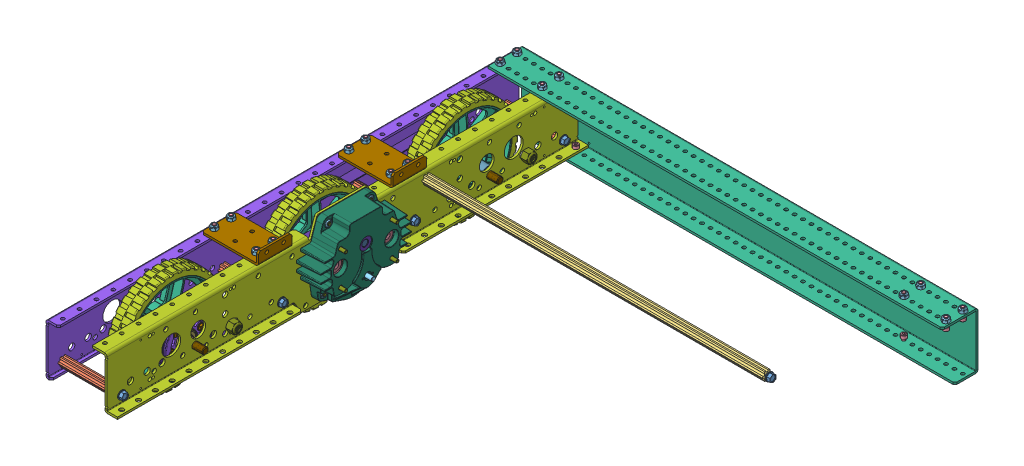
SolidWorks assembly AM14U3Square_Half, configuration Default. Lengths in mm.
Overall size (698.32 218.82 715.14).
150 component instances, 36 part files, 25 mates.
Components (placement in the parent):
- AM14U3Square_Frame_Half-1: AM14U3Square_Frame_Half [Default] at (326.068 37.2757 -291.2758) size (697.74 116.33 715.14)
  - ThreadRollingScrew_0.25-20x0.75-1: ThreadRollingScrew_0.25-20x0.75 [FHTS 0.25-20-G-0.75-C] at (-600.075 -67.437 693.039) x (-1 0 0) z (0 0.924225 0.381849) size (24.64 12.19 12.19)
  - ThreadRollingScrew_0.25-20x0.75-4: ThreadRollingScrew_0.25-20x0.75 [FHTS 0.25-20-G-0.75-C] at (-600.075 -67.437 26.035) x (-1 0 0) z (0 0.717495 0.696564) size (24.64 12.19 12.19)
  - ThreadRollingScrew_0.25-20x0.75-5: ThreadRollingScrew_0.25-20x0.75 [FHTS 0.25-20-G-0.75-C] at (-692.15 -67.437 26.162) size (24.64 12.19 12.19)
  - ThreadRollingScrew_0.25-20x0.75-7: ThreadRollingScrew_0.25-20x0.75 [FHTS 0.25-20-G-0.75-C] at (-603.25 -15.24 232.537) x (1 0 0) z (0 0.687398 0.726281) size (24.64 12.19 12.19)
  - ThreadRollingScrew_0.25-20x0.75-9: ThreadRollingScrew_0.25-20x0.75 [FHTS 0.25-20-G-0.75-C] at (-692.15 -67.437 692.912) size (24.64 12.19 12.19)
  - ThreadRollingScrew_0.25-20x0.75-10: ThreadRollingScrew_0.25-20x0.75 [FHTS 0.25-20-G-0.75-C] at (-82.55 -15.24 232.537) x (-1 0 0) z (0 0.525103 -0.851039) size (24.64 12.19 12.19)
  - 500Churro_3.375-1: 500Churro_3.375 [Default] at (-603.25 -67.437 26.162) x (0 -0.866025 0.5) z (-1 0 0) size (14.66 12.7 85.72)
  - 500Churro_3.375-2: 500Churro_3.375 [Default] at (-603.25 -67.437 692.912) x (0 -0.866025 0.5) z (-1 0 0) size (14.66 12.7 85.72)
  - 500Churro_cut_20.25-1: 500Churro_cut_20.25 [Default] at (-85.725 -15.24 232.537) x (0 0 -1) z (-1 0 0) size (14.66 12.7 514.35)
  - Screw_SHCS_10-32x0.5-19: Screw_SHCS_10-32x0.5 [HX-SHCS 0.19-32x1.375x1-C] at (-679.45 -11.176 42.037) x (0 1 0) z (0.542711 0 0.839919) size (17.53 7.94 7.94)
  - Screw_SHCS_10-32x0.5-20: Screw_SHCS_10-32x0.5 [HX-SHCS 0.19-32x1.375x1-C] at (-679.45 -11.176 16.637) x (0 1 0) z (0.127767 0 0.991804) size (17.53 7.94 7.94)
  - Screw_SHCS_10-32x0.5-21: Screw_SHCS_10-32x0.5 [HX-SHCS 0.19-32x1.375x1-C] at (-615.95 -11.176 16.637) x (0 1 0) z (0 0 1) size (17.53 7.94 7.94)
  - Screw_SHCS_10-32x0.5-22: Screw_SHCS_10-32x0.5 [HX-SHCS 0.19-32x1.375x1-C] at (-615.95 -11.176 42.037) x (0 1 0) z (0.337423 0 -0.941353) size (17.53 7.94 7.94)
  - Screw_SHCS_10-32x0.5-23: Screw_SHCS_10-32x0.5 [HX-SHCS 0.19-32x1.375x1-C] at (-590.55 -72.898 16.637) x (0 -1 0) z (0.717151 0 -0.696918) size (17.53 7.94 7.94)
  - Screw_SHCS_10-32x0.5-24: Screw_SHCS_10-32x0.5 [HX-SHCS 0.19-32x1.375x1-C] at (-6.35 -11.176 16.637) x (0 1 0) z (0.222581 0 0.974914) size (17.53 7.94 7.94)
  - Screw_SHCS_10-32x0.5-25: Screw_SHCS_10-32x0.5 [HX-SHCS 0.19-32x1.375x1-C] at (-6.35 -11.176 42.037) x (0 1 0) z (0.81526 0 0.579096) size (17.53 7.94 7.94)
  - Screw_SHCS_10-32x0.5-26: Screw_SHCS_10-32x0.5 [HX-SHCS 0.19-32x1.375x1-C] at (-69.85 -11.176 16.637) x (0 1 0) z (0 0 1) size (17.53 7.94 7.94)
  - Screw_SHCS_10-32x0.5-27: Screw_SHCS_10-32x0.5 [HX-SHCS 0.19-32x1.375x1-C] at (-69.85 -11.176 42.037) x (0 1 0) z (0.111454 0 0.99377) size (17.53 7.94 7.94)
  - Screw_SHCS_10-32x0.5-28: Screw_SHCS_10-32x0.5 [HX-SHCS 0.19-32x1.375x1-C] at (-95.25 -73.406 16.637) x (0 -1 0) z (0.007214 0 0.999974) size (17.53 7.94 7.94)
  - NylockNut_10-32-19: NylockNut_10-32 [Default] at (-679.45 0 42.037) x (0.996106 0 -0.088165) z (0 1 0) size (10.18 11.01 7.1)
  - NylockNut_10-32-21: NylockNut_10-32 [Default] at (-679.45 0 16.637) x (1 0 0) z (0 1 0) size (10.18 11.01 7.1)
  - NylockNut_10-32-22: NylockNut_10-32 [Default] at (-615.95 0 42.037) x (1 0 0) z (0 1 0) size (10.18 11.01 7.1)
  - NylockNut_10-32-23: NylockNut_10-32 [Default] at (-615.95 0 16.637) x (-0.398852 0 -0.917015) z (0 1 0) size (10.18 11.01 7.1)
  - NylockNut_10-32-25: NylockNut_10-32 [Default] at (-69.85 0 42.037) x (1 0 0) z (0 1 0) size (10.18 11.01 7.1)
  - NylockNut_10-32-26: NylockNut_10-32 [Default] at (-69.85 0 16.637) x (1 0 0) z (0 1 0) size (10.18 11.01 7.1)
  - NylockNut_10-32-27: NylockNut_10-32 [Default] at (-6.35 0 42.037) x (1 0 0) z (0 1 0) size (10.18 11.01 7.1)
  - NylockNut_10-32-28: NylockNut_10-32 [Default] at (-6.35 0 16.637) x (1 0 0) z (0 1 0) size (10.18 11.01 7.1)
  - NylockNut_10-32-29: NylockNut_10-32 [Default] at (-95.25 -84.582 16.637) x (1 0 0) z (0 -1 0) size (10.18 11.01 7.1)
  - NylockNut_10-32-30: NylockNut_10-32 [Default] at (-590.55 -84.582 16.637) x (1 0 0) z (0 -1 0) size (10.18 11.01 7.1)
  - Screw_SHCS_10-32x0.5-29: Screw_SHCS_10-32x0.5 [HX-SHCS 0.19-32x1.375x1-C] at (-679.45 -11.176 245.237) x (0 1 0) z (0.717626 0 0.696429) size (17.53 7.94 7.94)
  - Screw_SHCS_10-32x0.5-30: Screw_SHCS_10-32x0.5 [HX-SHCS 0.19-32x1.375x1-C] at (-679.45 -11.176 270.637) x (0 1 0) z (-0.597439 0 0.801914) size (17.53 7.94 7.94)
  - Screw_SHCS_10-32x0.5-31: Screw_SHCS_10-32x0.5 [HX-SHCS 0.19-32x1.375x1-C] at (-615.95 -11.176 245.237) x (0 1 0) z (0.931086 0 -0.3648) size (17.53 7.94 7.94)
  - Screw_SHCS_10-32x0.5-32: Screw_SHCS_10-32x0.5 [HX-SHCS 0.19-32x1.375x1-C] at (-615.95 -11.176 270.637) x (0 1 0) z (0.782299 0 0.622903) size (17.53 7.94 7.94)
  - Screw_SHCS_10-32x0.5-33: Screw_SHCS_10-32x0.5 [HX-SHCS 0.19-32x1.375x1-C] at (-615.95 -11.176 448.437) x (0 1 0) z (0 0 1) size (17.53 7.94 7.94)
  - Screw_SHCS_10-32x0.5-34: Screw_SHCS_10-32x0.5 [HX-SHCS 0.19-32x1.375x1-C] at (-615.95 -11.176 473.837) x (0 1 0) z (0 0 1) size (17.53 7.94 7.94)
  - Screw_SHCS_10-32x0.5-35: Screw_SHCS_10-32x0.5 [HX-SHCS 0.19-32x1.375x1-C] at (-679.45 -11.176 448.437) x (0 1 0) z (0 0 1) size (17.53 7.94 7.94)
  - Screw_SHCS_10-32x0.5-36: Screw_SHCS_10-32x0.5 [HX-SHCS 0.19-32x1.375x1-C] at (-679.45 -11.176 473.837) x (0 1 0) z (0 0 1) size (17.53 7.94 7.94)
  - NylockNut_10-32-31: NylockNut_10-32 [Default] at (-679.45 0 473.837) x (1 0 0) z (0 1 0) size (10.18 11.01 7.1)
  - NylockNut_10-32-32: NylockNut_10-32 [Default] at (-679.45 0 448.437) x (1 0 0) z (0 1 0) size (10.18 11.01 7.1)
  - NylockNut_10-32-33: NylockNut_10-32 [Default] at (-615.95 0 448.437) x (1 0 0) z (0 1 0) size (10.18 11.01 7.1)
  - NylockNut_10-32-34: NylockNut_10-32 [Default] at (-615.95 0 473.837) x (1 0 0) z (0 1 0) size (10.18 11.01 7.1)
  - NylockNut_10-32-35: NylockNut_10-32 [Default] at (-679.45 0 270.637) x (1 0 0) z (0 1 0) size (10.18 11.01 7.1)
  - NylockNut_10-32-37: NylockNut_10-32 [Default] at (-679.45 0 245.237) x (1 0 0) z (0 1 0) size (10.18 11.01 7.1)
  - NylockNut_10-32-38: NylockNut_10-32 [Default] at (-615.95 0 270.637) x (-0.99946 0 -0.032874) z (0 1 0) size (10.18 11.01 7.1)
  - NylockNut_10-32-39: NylockNut_10-32 [Default] at (-615.95 0 245.237) x (-0.973817 0 0.227332) z (0 1 0) size (10.18 11.01 7.1)
  - AM14U3EndPlate_Square-1: AM14U3EndPlate_Square [Default] at (-787.4 -81.407 0) x (1 0 0) z (0 -1 0) size (685.8 53.98 84.58)
  - AM14U3InnerPlate_Square-1: AM14U3InnerPlate_Square [Default] at (-603.25 -76.962 765.937) x (0 0 -1) z (0 -1 0) size (711.2 38.1 116.33)
  - AM14U3OuterPlate_Square-1: AM14U3OuterPlate_Square [Default] at (-667.7485 -26.7681 75.5865) x (0 0 1) z (0 -1 0) size (711.2 19.05 77.72)
  - Bracket_2x3-1: Bracket_2x3 [Default] at (-685.8 -3.175 499.237) size (85.72 19.05 50.8)
  - Bracket_2x3-2: Bracket_2x3 [Default] at (-685.8 -3.175 296.037) size (85.72 19.05 50.8)
  - 500Churro_3.375-5: 500Churro_3.375 [Default] at (-688.975 -66.675 451.612) x (0 0 -1) z (1 0 0) size (14.66 12.7 85.72)
  - 500Churro_3.375-6: 500Churro_3.375 [Default] at (-688.975 -59.4147 252.0115) x (0 0.995852 0.090991) z (1 0 0) size (14.66 12.7 85.72)
  - ThreadRollingScrew_0.25-20x0.75-11: ThreadRollingScrew_0.25-20x0.75 [FHTS 0.25-20-G-0.75-C] at (-600.075 -66.675 451.612) x (-1 0 0) z (0 0.997671 0.06821) size (24.64 12.19 12.19)
  - ThreadRollingScrew_0.25-20x0.75-12: ThreadRollingScrew_0.25-20x0.75 [FHTS 0.25-20-G-0.75-C] at (-600.075 -59.4147 252.0115) x (-1 0 0) z (0 -0.62596 0.779855) size (24.64 12.19 12.19)
  - ThreadRollingScrew_0.25-20x0.75-13: ThreadRollingScrew_0.25-20x0.75 [FHTS 0.25-20-G-0.75-C] at (-692.15 -66.675 451.612) size (24.64 12.19 12.19)
  - ThreadRollingScrew_0.25-20x0.75-14: ThreadRollingScrew_0.25-20x0.75 [FHTS 0.25-20-G-0.75-C] at (-692.15 -66.675 267.462) size (24.64 12.19 12.19)
- ToughboxMini-1: ToughboxMini [Default] at (-324.5487 -32.4844 159.362) x (0 0.001296 0.999999) z (-1 0 0) size (140.05 122.78 142.29) (flexible)
  - TBMiniSmallHexShaft-1: TBMiniSmallHexShaft [Default] at (-75.0534 90.4124 -52.3959) x (-0.017391 0.999849 0) z (0.999849 0.017391 0) size (11 38.23 9.52)
  - LargeClusterGear_Hex_50t0.375-1: LargeClusterGear_Hex_50t0.375 [Default] at (-91.0349 50.9043 -67.5597) x (-0.017391 0.999849 0) z (0 0 -1) size (65.97 66.04 10.16)
  - Bearing_FR6ZZ-1: Bearing_FR6ZZ [Default] at (-96.247 60.278 -52.5991) x (-0.893862 0.448342 0) z (0 0 1) size (24.69 24.69 7.16)
  - NylockNut_10-32-1: NylockNut_10-32 [Default] at (-129.8464 -8.0737 -56.3837) x (0.501678 0.865055 0) z (0 0 -1) size (10.18 11.01 7.1)
  - NylockNut_10-32-2: NylockNut_10-32 [Default] at (-59.2462 80.7349 -56.3837) x (0.999999 -0.001296 0) z (0 0 -1) size (10.18 11.01 7.1)
  - NylockNut_10-32-3: NylockNut_10-32 [Default] at (-122.7461 80.8172 -56.3837) x (0.500567 0.865698 0) z (0 0 -1) size (10.18 11.01 7.1)
  - NylockNut_10-32-4: NylockNut_10-32 [Default] at (-52.3764 -8.1741 -56.3837) x (-0.501678 -0.865055 0) z (0 0 -1) size (10.18 11.01 7.1)
  - Washer_5-16-1: Washer_5-16 [Default] at (-52.3162 38.3079 -77.7705) x (-0.418041 0.908428 0) z (0 0 -1) size (17.53 17.53 1.47)
  - Washer_5-16-2: Washer_5-16 [Default] at (-52.3162 38.3079 -76.2973) x (0.897267 -0.441488 0) z (0 0 -1) size (17.53 17.53 1.47)
  - Washer_5-16-3: Washer_5-16 [Default] at (-129.7861 38.4083 -77.7705) x (-0.990116 0.140253 0) z (0 0 1) size (17.53 17.53 1.47)
  - Washer_5-16-4: Washer_5-16 [Default] at (-129.7861 38.4083 -79.2437) x (-0.681761 0.731575 0) z (0 0 1) size (17.53 17.53 1.47)
  - CIMGear_14t8mm-1: CIMGear_14t8mm [Default] at (-52.3162 38.3079 -63.5973) x (0.95671 0.291041 0) z (0 0 -1) size (20.03 20.32 12.7)
  - CIMGear_14t8mm-2: CIMGear_14t8mm [Default] at (-129.7861 38.4083 -63.5973) x (0.906804 -0.421552 0) z (0 0 -1) size (20.03 20.32 12.7)
  - TBMiniHousing-1: TBMiniHousing [Default] at (-91.0876 10.1882 -86.3557) x (0.999999 -0.001296 0) z (0 0 1) size (139.9 118.55 41.54)
  - Screw_SHCS_10-32x0.625-1: Screw_SHCS_10-32x0.625 [Default] at (-52.2832 63.7078 -74.4685) x (-0.564778 -0.825243 0) z (-0.825243 0.564778 0) size (7.82 20.65 7.82)
  - Screw_SHCS_10-32x0.625-2: Screw_SHCS_10-32x0.625 [Default] at (-122.7461 80.8172 -42.5915) x (0.507484 -0.861661 0) z (-0.861661 -0.507484 0) size (7.82 20.65 7.82)
  - Screw_SHCS_10-32x0.625-3: Screw_SHCS_10-32x0.625 [Default] at (-52.3764 -8.1741 -42.5915) x (0.507484 -0.861661 0) z (-0.861661 -0.507484 0) size (7.82 20.65 7.82)
  - Screw_SHCS_10-32x0.625-4: Screw_SHCS_10-32x0.625 [Default] at (-129.8464 -8.0737 -42.5915) x (0.507484 -0.861661 0) z (-0.861661 -0.507484 0) size (7.82 20.65 7.82)
  - Screw_SHCS_10-32x0.625-5: Screw_SHCS_10-32x0.625 [Default] at (-59.2462 80.7349 -42.5915) x (0.740711 -0.671824 0) z (-0.671824 -0.740711 0) size (7.82 20.65 7.82)
  - Screw_SHCS_10-32x0.625-6: Screw_SHCS_10-32x0.625 [Default] at (-52.3491 12.9079 -74.4685) x (-0.564778 -0.825243 0) z (-0.825243 0.564778 0) size (7.82 20.65 7.82)
  - Screw_SHCS_10-32x0.625-7: Screw_SHCS_10-32x0.625 [Default] at (-129.7532 63.8083 -74.4685) x (-0.966277 -0.257503 0) z (-0.257503 0.966277 0) size (7.82 20.65 7.82)
  - Screw_SHCS_10-32x0.625-8: Screw_SHCS_10-32x0.625 [Default] at (-129.819 13.0083 -74.4685) x (-0.99652 0.083357 0) z (0.083357 0.99652 0) size (7.82 20.65 7.82)
  - Bearing_R6ZZ-3: Bearing_R6ZZ [Default] at (-91.0349 50.9043 -84.8317) x (0.958138 -0.286306 0) z (0 0 1) size (22.23 22.23 7.11)
  - Bearing_R6ZZ-4: Bearing_R6ZZ [Default] at (-91.0876 10.1882 -84.8317) x (-0.661529 0.74992 0) z (0 0 1) size (22.23 22.23 7.11)
  - RetainingClip-1: RetainingClip [Default] at (-129.7861 38.4083 -63.5973) x (0 0 1) z (-1 0 0) size (1.09 14.83 14.83)
  - RetainingClip-2: RetainingClip [Default] at (-52.3162 38.3079 -63.5973) x (0 0 1) z (-1 0 0) size (1.09 14.83 14.83)
  - ExternalKlipring-1: ExternalKlipring [Default] at (-91.0876 10.1882 -64.4355) x (0.996411 -0.084651 0) z (0 0 1) size (19.07 20.96 1.27)
  - HexBearing_FR8ZZ-1: HexBearing_FR8ZZ [Default] at (-91.0876 10.1882 -44.6717) x (0.029036 0.999578 0) z (0 0 -1) size (31.12 31.12 7.93)
  - SmallClusterGear_Hex_16t0.375-1: SmallClusterGear_Hex_16t0.375 [Default] at (-91.0349 50.9043 -67.5597) x (0 0 1) z (-0.87459 0.484863 0) size (15.19 22.57 22.57)
  - LargeOutputGear_Hex_48t0.5-1: LargeOutputGear_Hex_48t0.5 [Default] at (-91.0876 10.1882 -63.1655) x (0 0 1) z (-0.880178 -0.474644 0) size (10.21 63.42 63.42)
  - TBMiniHexOutputShaft-2: TBMiniHexOutputShaft [Default] at (-73.3134 47.9951 -52.3197) x (0.029036 0.999578 0) z (0.999578 -0.029036 0) size (14.66 142.29 12.7)
- Wheel_6inHiGrip_Center-1: Wheel_6inHiGrip_Center [Default] at (-288.1818 -17.7898 -84.7378) x (-1 0 0) z (0 0.475784 0.879562) size (81.42 191.55 191.55) (flexible)
  - Wheel_6inHiGrip-1: Wheel_6inHiGrip [Default] at (83.7987 67.439 110.9939) size (35.05 191.55 191.55)
    - Wheel_6inHiGrip_Wheel-1: Wheel_6inHiGrip_Wheel [Default] at (-52.6446 9.4231 21.378) size (35.05 132.08 132.08)
    - Wheel_6inHiGrip_Tread-1: Wheel_6inHiGrip_Tread [Default] at (-65.3446 9.4231 21.378) x (0 -0.304368 -0.952555) z (1 0 0) size (152.4 152.4 25.58)
  - HalfPulley_42t5mm-1: HalfPulley_42t5mm [Default] at (47.6006 76.862 132.3719) x (1 0 0) z (0 -0.5 0.866025) size (13 74.23 74.23)
  - HalfPulley_42t5mm-2: HalfPulley_42t5mm [Default] at (64.263 76.862 132.3719) x (-1 0 0) z (0 -0.499927 0.866067) size (13 74.23 74.23)
  - ThreadFormingScrew_10-24x1.25-1: ThreadFormingScrew_10-24x1.25 [93882A213] at (63.247 76.8605 108.5602) x (0 -0.67777 0.735274) z (1 0 0) size (10.52 10.52 35.59)
  - ThreadFormingScrew_10-24x1.25-2: ThreadFormingScrew_10-24x1.25 [93882A213] at (63.247 97.4833 120.4656) x (0 -0.67777 0.735274) z (1 0 0) size (10.52 10.52 35.59)
  - ThreadFormingScrew_10-24x1.25-3: ThreadFormingScrew_10-24x1.25 [93882A213] at (63.247 56.2398 144.2799) x (0 -0.67777 0.735274) z (1 0 0) size (10.52 10.52 35.59)
  - ThreadFormingScrew_10-24x1.25-4: ThreadFormingScrew_10-24x1.25 [93882A213] at (63.247 76.8625 156.1852) x (0 0.509671 0.860369) z (1 0 0) size (10.52 10.52 35.59)
  - ThreadFormingScrew_10-24x1.25-5: ThreadFormingScrew_10-24x1.25 [93882A213] at (63.247 97.4843 144.2781) x (0 0.974333 0.225112) z (1 0 0) size (10.52 10.52 35.59)
  - ThreadFormingScrew_10-24x1.25-6: ThreadFormingScrew_10-24x1.25 [93882A213] at (63.247 56.2388 120.4674) x (0 0.101244 0.994862) z (1 0 0) size (10.52 10.52 35.59)
  - HalfPulley_42t5mm-3: HalfPulley_42t5mm [Default] at (-1.9548 76.862 132.3719) x (1 0 0) z (0 -1 -0.000063) size (13 74.23 74.23)
  - HalfPulley_42t5mm-4: HalfPulley_42t5mm [Default] at (14.7076 76.862 132.3719) x (-1 0 0) z (0 -1 0.000021) size (13 74.23 74.23)
  - HexHub_500EX-1: HexHub_500EX [Default] at (-8.3048 76.862 132.3719) x (0 -0.866025 -0.5) z (0 -0.5 0.866025) size (55.37 25.4 51.33)
  - ThreadFormingScrew_10-24x1.25-7: ThreadFormingScrew_10-24x1.25 [93882A213] at (-5.2568 97.4843 120.4656) x (0 0.67777 -0.735274) z (-1 0 0) size (10.52 10.52 35.59)
  - ThreadFormingScrew_10-24x1.25-8: ThreadFormingScrew_10-24x1.25 [93882A213] at (-5.2568 76.862 108.5594) x (0 0.67777 -0.735274) z (-1 0 0) size (10.52 10.52 35.59)
  - ThreadFormingScrew_10-24x1.25-9: ThreadFormingScrew_10-24x1.25 [93882A213] at (-5.2568 56.2398 120.4656) x (0 0.67777 -0.735274) z (-1 0 0) size (10.52 10.52 35.59)
  - ThreadFormingScrew_10-24x1.25-10: ThreadFormingScrew_10-24x1.25 [93882A213] at (-5.2568 97.4843 144.2781) x (0 0.654955 0.755668) z (-1 0 0) size (10.52 10.52 35.59)
  - ThreadFormingScrew_10-24x1.25-11: ThreadFormingScrew_10-24x1.25 [93882A213] at (-5.2568 56.2398 144.2781) x (0 0.773336 -0.633996) z (-1 0 0) size (10.52 10.52 35.59)
  - ThreadFormingScrew_10-24x1.25-12: ThreadFormingScrew_10-24x1.25 [93882A213] at (-5.2568 76.862 156.1844) x (0 0.622324 0.782759) z (-1 0 0) size (10.52 10.52 35.59)
  - Spacer_Hex_0.57x0.5-1: Spacer_Hex_0.57x0.5 [Default] at (57.8495 76.862 132.3719) x (0 -0.866025 -0.5) z (0 -0.5 0.866025) size (28.55 14.48 28.55)
- Wheel-6inHiGrip_Outer-1: Wheel-6inHiGrip_Outer [Default] at (-351.6685 85.441 180.4563) x (1 0 0) z (0 -0.96131 0.275469) size (85.56 191.55 191.55)
  - Wheel_6inHiGrip-1: Wheel_6inHiGrip [Default] at (83.7987 67.439 110.9939) size (35.05 191.55 191.55)
    - Wheel_6inHiGrip_Wheel-1: Wheel_6inHiGrip_Wheel [Default] at (-52.6446 9.4231 21.378) size (35.05 132.08 132.08)
    - Wheel_6inHiGrip_Tread-1: Wheel_6inHiGrip_Tread [Default] at (-65.3446 9.4231 21.378) x (0 -0.304368 -0.952555) z (1 0 0) size (152.4 152.4 25.58)
  - HalfPulley_42t5mm-1: HalfPulley_42t5mm [Default] at (47.6006 76.862 132.3719) x (1 0 0) z (0 -0.5 0.866025) size (13 74.23 74.23)
  - HalfPulley_42t5mm-2: HalfPulley_42t5mm [Default] at (64.263 76.862 132.3719) x (-1 0 0) z (0 -0.499927 0.866067) size (13 74.23 74.23)
  - Bearing_1614ZZ-1: Bearing_1614ZZ [Default] at (62.612 76.862 132.3719) x (0 -0.157148 -0.987575) z (-1 0 0) size (28.57 28.57 9.53)
  - Bearing_1614ZZ-2: Bearing_1614ZZ [Default] at (15.2791 76.862 132.3719) x (0 0 -1) z (1 0 0) size (28.57 28.57 9.53)
  - ThreadFormingScrew_10-24x1.25-1: ThreadFormingScrew_10-24x1.25 [93882A213] at (63.247 76.8605 108.5602) x (0 0 -1) z (1 0 0) size (10.52 10.52 35.59)
  - ThreadFormingScrew_10-24x1.25-2: ThreadFormingScrew_10-24x1.25 [93882A213] at (63.247 97.4833 120.4656) x (0 0 -1) z (1 0 0) size (10.52 10.52 35.59)
  - ThreadFormingScrew_10-24x1.25-3: ThreadFormingScrew_10-24x1.25 [93882A213] at (63.247 56.2398 144.2799) x (0 0 -1) z (1 0 0) size (10.52 10.52 35.59)
  - ThreadFormingScrew_10-24x1.25-4: ThreadFormingScrew_10-24x1.25 [93882A213] at (63.247 76.8625 156.1852) x (0 -0.95788 -0.287168) z (1 0 0) size (10.52 10.52 35.59)
  - ThreadFormingScrew_10-24x1.25-5: ThreadFormingScrew_10-24x1.25 [93882A213] at (63.247 97.4843 144.2781) x (0 -0.868976 0.494854) z (1 0 0) size (10.52 10.52 35.59)
  - ThreadFormingScrew_10-24x1.25-6: ThreadFormingScrew_10-24x1.25 [93882A213] at (63.247 56.2388 120.4674) x (0 -0.977348 -0.211637) z (1 0 0) size (10.52 10.52 35.59)
  - Spacer_0.28x0.382-1: Spacer_0.28x0.382 [Default] at (74.4865 76.862 132.3719) x (0 -0.35357 0.935408) z (-1 0 0) size (13.16 13.16 7.11)
  - Spacer_0.85x0.38-1: Spacer_0.85x0.38 [Default] at (-11.0734 76.862 132.3719) x (0 0 -1) z (1 0 0) size (19.05 19.05 21.59)
- Wheel-6inHiGrip_Outer-2: Wheel-6inHiGrip_Outer [Default] at (-288.2554 114.8369 -225.5401) x (-1 0 0) z (0 -0.531631 0.846976) size (85.56 191.55 191.55)
  - Wheel_6inHiGrip-1: Wheel_6inHiGrip [Default] at (83.7987 67.439 110.9939) size (35.05 191.55 191.55)
    - Wheel_6inHiGrip_Wheel-1: Wheel_6inHiGrip_Wheel [Default] at (-52.6446 9.4231 21.378) size (35.05 132.08 132.08)
    - Wheel_6inHiGrip_Tread-1: Wheel_6inHiGrip_Tread [Default] at (-65.3446 9.4231 21.378) x (0 -0.304368 -0.952555) z (1 0 0) size (152.4 152.4 25.58)
  - HalfPulley_42t5mm-1: HalfPulley_42t5mm [Default] at (47.6006 76.862 132.3719) x (1 0 0) z (0 -0.5 0.866025) size (13 74.23 74.23)
  - HalfPulley_42t5mm-2: HalfPulley_42t5mm [Default] at (64.263 76.862 132.3719) x (-1 0 0) z (0 -0.499927 0.866067) size (13 74.23 74.23)
  - Bearing_1614ZZ-1: Bearing_1614ZZ [Default] at (62.612 76.862 132.3719) x (0 -0.157148 -0.987575) z (-1 0 0) size (28.57 28.57 9.53)
  - Bearing_1614ZZ-2: Bearing_1614ZZ [Default] at (15.2791 76.862 132.3719) x (0 0 -1) z (1 0 0) size (28.57 28.57 9.53)
  - ThreadFormingScrew_10-24x1.25-1: ThreadFormingScrew_10-24x1.25 [93882A213] at (63.247 76.8605 108.5602) x (0 0 -1) z (1 0 0) size (10.52 10.52 35.59)
  - ThreadFormingScrew_10-24x1.25-2: ThreadFormingScrew_10-24x1.25 [93882A213] at (63.247 97.4833 120.4656) x (0 0 -1) z (1 0 0) size (10.52 10.52 35.59)
  - ThreadFormingScrew_10-24x1.25-3: ThreadFormingScrew_10-24x1.25 [93882A213] at (63.247 56.2398 144.2799) x (0 0 -1) z (1 0 0) size (10.52 10.52 35.59)
  - ThreadFormingScrew_10-24x1.25-4: ThreadFormingScrew_10-24x1.25 [93882A213] at (63.247 76.8625 156.1852) x (0 -0.95788 -0.287168) z (1 0 0) size (10.52 10.52 35.59)
  - ThreadFormingScrew_10-24x1.25-5: ThreadFormingScrew_10-24x1.25 [93882A213] at (63.247 97.4843 144.2781) x (0 -0.868976 0.494854) z (1 0 0) size (10.52 10.52 35.59)
  - ThreadFormingScrew_10-24x1.25-6: ThreadFormingScrew_10-24x1.25 [93882A213] at (63.247 56.2388 120.4674) x (0 -0.977348 -0.211637) z (1 0 0) size (10.52 10.52 35.59)
  - Spacer_0.28x0.382-1: Spacer_0.28x0.382 [Default] at (74.4865 76.862 132.3719) x (0 -0.35357 0.935408) z (-1 0 0) size (13.16 13.16 7.11)
  - Spacer_0.85x0.38-1: Spacer_0.85x0.38 [Default] at (-11.0734 76.862 132.3719) x (0 0 -1) z (1 0 0) size (19.05 19.05 21.59)
- Bearing_Hex_FR8ZZ-1: Bearing_Hex_FR8ZZ [Default] at (-369.3104 -22.4143 68.2612) x (0 -0.523831 0.851822) z (1 0 0) size (31.12 31.12 7.93)
- NylockNut_0.375-16-1: NylockNut_0.375-16 [91831A127] at (-274.007 -20.8903 236.8339) x (0 -1 0) z (0 0 1) size (14.29 12 16.5)
- NylockNut_0.375-16-2: NylockNut_0.375-16 [91831A127] at (-274.007 -20.8903 -208.2615) x (0 -1 0) z (0 0 1) size (14.29 12 16.5)
- Belt_15mm_Square-1: Belt_15mm_Square [Default] at (-289.0679 -20.6363 290.8089) x (0 -0.007989 -0.999968) z (-1 0 0) size (291.74 69.19 15)
- Belt_15mm_Square-2: Belt_15mm_Square [Default] at (-335.856 -20.6363 -154.2865) x (0 -0.007989 0.999968) z (-1 0 0) size (291.74 69.19 15)
- HHSBolt_0.375-16x4.25-3: HHSBolt_0.375-16x4.25 [HFBOLT 0.375-16x2.5x1-C] at (-372.2542 -20.6363 290.8089) x (1 0 0) z (0 0.54705 -0.8371) size (114.12 16.48 14.27)
- HHSBolt_0.375-16x4.25-4: HHSBolt_0.375-16x4.25 [HFBOLT 0.375-16x2.5x1-C] at (-372.2542 -20.6363 -154.2865) x (1 0 0) z (0 -0.961423 -0.275075) size (114.12 16.48 14.27)
Mates (geometry in assembly coordinates):
- Concentric1: concentric anti-aligned: cylinder of ToughboxMini-1/HexBearing_FR8ZZ-1 through (-271.9496 -22.4143 68.2612) axis (-1 0 0) radius 14.2875; cylinder of AM14U3Square_Frame_Half-1/AM14U3InnerPlate_Square-1 through (-277.182 -22.4143 68.2612) axis (1 0 0) radius 14.2875
- Parallel1: parallel: line of ToughboxMini-1/TBMiniHousing-1 through (-273.4813 57.1529 36.5112) axis (0 0 1); plane of AM14U3Square_Frame_Half-1/AM14U3InnerPlate_Square-1 through (-274.007 57.5957 20.6362) normal (0 1 0)
- Coincident2: coincident anti-aligned: plane of AM14U3Square_Frame_Half-1/AM14U3InnerPlate_Square-1 through (-274.007 30.1637 474.6612) normal (1 0 0); plane of ToughboxMini-1/TBMiniHousing-1 through (-274.007 -22.4143 68.2612) normal (-1 0 0)
- Concentric2: concentric anti-aligned: cylinder of AM14U3Square_Frame_Half-1/AM14U3OuterPlate_Square-1 through (-254.956 -20.6363 290.8089) axis (-1 0 0) radius 4.826; cylinder of Wheel-6inHiGrip_Outer-1/Spacer_0.28x0.382-1 through (-284.294 -20.6363 290.8089) axis (1 0 0) radius 6.5786
- Coincident3: coincident anti-aligned: plane of AM14U3Square_Frame_Half-1/AM14U3InnerPlate_Square-1 through (-277.182 30.1637 474.6612) normal (-1 0 0); plane of Wheel-6inHiGrip_Outer-1/Spacer_0.28x0.382-1 through (-277.182 -20.6363 290.8089) normal (1 0 0)
- Concentric3: concentric aligned: cylinder of Wheel-6inHiGrip_Outer-2/Spacer_0.28x0.382-1 through (-355.6299 -20.6363 -154.2865) axis (-1 0 0) radius 6.5786; cylinder of HHSBolt_0.375-16x4.25-4 through (-372.2542 -20.6363 -154.2865) axis (-1 0 0) radius 4.7625
- Coincident4: coincident anti-aligned: plane of AM14U3Square_Frame_Half-1/AM14U3InnerPlate_Square-1 through (-277.182 30.1637 474.6612) normal (-1 0 0); plane of Wheel-6inHiGrip_Outer-2/Spacer_0.85x0.38-1 through (-277.182 -20.6363 -154.2865) normal (1 0 0)
- Concentric4: concentric anti-aligned: cylinder of ToughboxMini-1/HexBearing_FR8ZZ-1 through (-271.9496 -22.4143 68.2612) axis (-1 0 0) radius 14.2875; cylinder of Wheel_6inHiGrip_Center-1/Spacer_Hex_0.57x0.5-1 through (-360.5093 -22.4143 68.2612) axis (1 0 0) radius 14.2748
- Parallel2: parallel anti-aligned: plane of ToughboxMini-1/TBMiniHexOutputShaft-2 through (-246.829 -29.7439 68.0578) normal (0 -0.879562 0.475784); plane of Wheel_6inHiGrip_Center-1/HexHub_500EX-1 through (-279.877 -29.7585 68.0574) normal (0 0.879562 -0.475784)
- Coincident6: coincident anti-aligned: plane of ToughboxMini-1/HexBearing_FR8ZZ-1 through (-279.877 -22.4143 68.2612) normal (-1 0 0); plane of Wheel_6inHiGrip_Center-1/HexHub_500EX-1 through (-279.877 -22.4143 68.2612) normal (1 0 0)
- Concentric51: concentric aligned: cylinder of AM14U3Square_Frame_Half-1/AM14U3OuterPlate_Square-1 through (-362.907 -22.4143 68.2612) axis (-1 0 0) radius 14.2875; cylinder of Bearing_Hex_FR8ZZ-1 through (-361.383 -22.4143 68.2612) axis (-1 0 0) radius 13.97
- Coincident71: coincident anti-aligned: plane of AM14U3Square_Frame_Half-1/AM14U3OuterPlate_Square-1 through (-362.907 30.1637 -338.1388) normal (1 0 0); plane of Bearing_Hex_FR8ZZ-1 through (-362.907 -29.7322 80.1611) normal (-1 0 0)
- Coincident8: coincident anti-aligned: plane of ToughboxMini-1/TBMiniHexOutputShaft-2 through (-246.829 -29.7439 68.0578) normal (0 -0.879562 0.475784); plane of Bearing_Hex_FR8ZZ-1 through (-361.383 -29.7439 68.0578) normal (0 0.879562 -0.475784)
- Coincident11: coincident anti-aligned: plane of AM14U3Square_Frame_Half-1/AM14U3InnerPlate_Square-1 through (-274.007 30.1637 474.6612) normal (1 0 0); plane of NylockNut_0.375-16-1 through (-274.007 -13.7466 224.4605) normal (-1 0 0)
- Coincident12: coincident anti-aligned: plane of AM14U3Square_Frame_Half-1/AM14U3InnerPlate_Square-1 through (-274.007 30.1637 474.6612) normal (1 0 0); plane of NylockNut_0.375-16-2 through (-274.007 -13.7466 -220.6349) normal (-1 0 0)
- Concentric11: concentric anti-aligned: cylinder of Wheel-6inHiGrip_Outer-1/Spacer_0.85x0.38-1 through (-341.1519 -20.6363 290.8089) axis (-1 0 0) radius 9.525; cylinder of Belt_15mm_Square-1 through (-304.0679 -20.6363 290.8089) axis (1 0 0) radius 33.4264
- Concentric12: concentric anti-aligned: cylinder of Bearing_Hex_FR8ZZ-1 through (-361.383 -22.4143 68.2612) axis (-1 0 0) radius 14.2875; cylinder of Belt_15mm_Square-1 through (-304.0679 -22.4143 68.2612) axis (1 0 0) radius 33.4264
- Coincident13: coincident anti-aligned: plane of Wheel-6inHiGrip_Outer-1/HalfPulley_42t5mm-1 through (-304.0679 -20.6363 290.8089) normal (1 0 0); plane of Belt_15mm_Square-1 through (-304.0679 -20.6363 290.8089) normal (-1 0 0)
- Concentric13: concentric anti-aligned: cylinder of Bearing_Hex_FR8ZZ-1 through (-361.383 -22.4143 68.2612) axis (-1 0 0) radius 14.2875; cylinder of Belt_15mm_Square-2 through (-350.856 -22.4143 68.2612) axis (1 0 0) radius 33.4264
- Concentric14: concentric aligned: cylinder of Wheel-6inHiGrip_Outer-2/Spacer_0.85x0.38-1 through (-298.772 -20.6363 -154.2865) axis (1 0 0) radius 9.525; cylinder of Belt_15mm_Square-2 through (-350.856 -20.6363 -154.2865) axis (1 0 0) radius 33.4264
- Coincident14: coincident anti-aligned: plane of Wheel-6inHiGrip_Outer-2/HalfPulley_42t5mm-1 through (-335.856 -20.6363 -154.2865) normal (-1 0 0); plane of Belt_15mm_Square-2 through (-335.856 -20.6363 -154.2865) normal (1 0 0)
- Concentric72: concentric aligned: cylinder of AM14U3Square_Frame_Half-1/AM14U3OuterPlate_Square-1 through (-254.956 -20.6363 290.8089) axis (-1 0 0) radius 4.826; cylinder of HHSBolt_0.375-16x4.25-3 through (-372.2542 -20.6363 290.8089) axis (-1 0 0) radius 4.7625
- Coincident102: coincident anti-aligned: plane of AM14U3Square_Frame_Half-1/AM14U3OuterPlate_Square-1 through (-366.082 30.1637 -338.1388) normal (-1 0 0); plane of HHSBolt_0.375-16x4.25-3 through (-366.082 -27.5353 286.3003) normal (1 0 0)
- Concentric731: concentric aligned: cylinder of AM14U3Square_Frame_Half-1/AM14U3OuterPlate_Square-1 through (-254.956 -20.6363 -154.2865) axis (-1 0 0) radius 4.826; cylinder of HHSBolt_0.375-16x4.25-4 through (-372.2542 -20.6363 -154.2865) axis (-1 0 0) radius 7.1374
- Coincident1031: coincident anti-aligned: plane of AM14U3Square_Frame_Half-1/AM14U3OuterPlate_Square-1 through (-366.082 30.1637 -338.1388) normal (-1 0 0); plane of HHSBolt_0.375-16x4.25-4 through (-366.082 -22.9034 -146.3629) normal (1 0 0)
